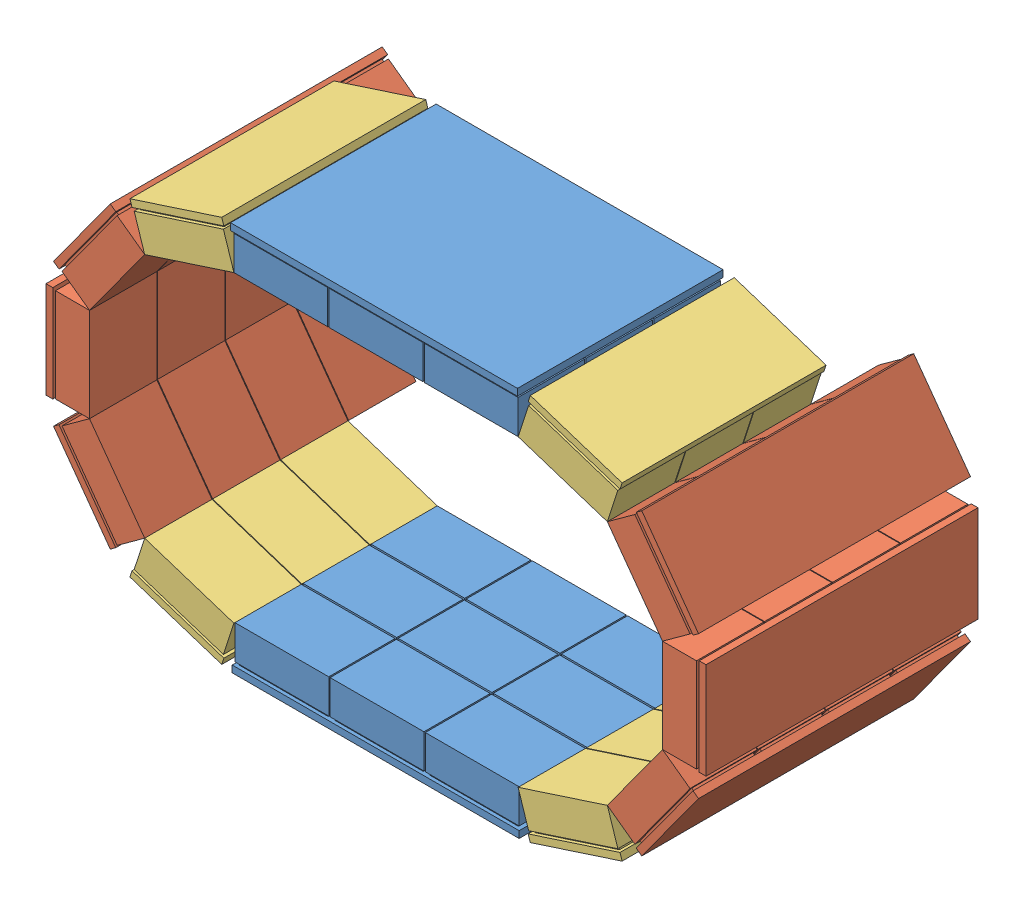
SolidWorks assembly Detector1n2_3_changed, configuration Default. Lengths in mm.
Overall size (565.24 340.33 201.48).
14 component instances, 3 part files, 18 mates.
Components (placement in the parent):
- top_bottomDetector3-2: top_bottomDetector3 [Default] at (-106.7647 78.2438 -235.0736) size (211 32 151.22)
- CshapedDetector2-3: CshapedDetector2 [Default] at (62.2764 -58.5479 -394.5758) x (0.951057 0.309017 0) z (0 0 1) size (177.89 270.84 200)
  - 1Detector-2: 1Detector [Default] at (173.0714 153.2337 184.2598) x (0.809017 0.587785 0) z (0 0 1) size (71 32 200)
  - 1Detector-4: 1Detector [Default] at (223.2683 222.3237 184.2598) x (0.309017 0.951057 0) z (0 0 1) size (71 32 200)
  - 1Detector-5: 1Detector [Default] at (223.2683 307.7237 184.2598) x (-0.309017 0.951057 0) z (0 0 1) size (71 32 200)
  - 1Detector_3modules-1: 1Detector_3modules [Default] at (91.8512 126.8436 209.2598) size (71 32 150)
  - 1Detector_3modules-2: 1Detector_3modules [Default] at (173.0714 376.8138 209.2598) x (-0.809017 0.587785 0) z (0 0 1) size (71 32 150)
- CshapedDetector2-4: CshapedDetector2 [Default] at (-135.8058 502.3243 -394.5758) x (-0.951057 -0.309017 0) z (0 0 1) size (177.89 270.84 200)
  - 1Detector-2: 1Detector [Default] at (173.0714 153.2337 184.2598) x (0.809017 0.587785 0) z (0 0 1) size (71 32 200)
  - 1Detector-4: 1Detector [Default] at (223.2683 222.3237 184.2598) x (0.309017 0.951057 0) z (0 0 1) size (71 32 200)
  - 1Detector-5: 1Detector [Default] at (223.2683 307.7237 184.2598) x (-0.309017 0.951057 0) z (0 0 1) size (71 32 200)
  - 1Detector_3modules-1: 1Detector_3modules [Default] at (91.8512 126.8436 209.2598) size (71 32 150)
  - 1Detector_3modules-2: 1Detector_3modules [Default] at (173.0714 376.8138 209.2598) x (-0.809017 0.587785 0) z (0 0 1) size (71 32 150)
- top_bottomDetector3-3: top_bottomDetector3 [Default] at (-106.7647 365.5325 -135.0585) x (1 0 0) z (0 0 -1) size (211 32 151.22)
Mates (geometry in assembly coordinates):
- Coincident2: coincident anti-aligned: line of ? through (109.8043 92.2155 198.3608) axis (0 0 -1); line of ? through (109.8043 92.2155 148.8608) axis (0 0 1)
- Angle1: planar angle = 3.455752 rad anti-aligned: line of ? through (40.8043 92.2155 198.3608) axis (1 0 0); line of ? through (109.8043 92.2155 198.3608) axis (0.951057 0.309017 0)
- Coincident4: coincident: point of ?; point of ?
- Coincident5: coincident anti-aligned: line of ? through (-29.1957 92.2155 149.6059) axis (0 0 1); line of ? through (-29.1957 92.2155 198.3608) axis (0 0 -1)
- Angle2: planar angle = 3.455752 rad anti-aligned: line of ? through (-94.8186 113.5376 198.3608) axis (0.951057 -0.309017 0); line of ? through (-29.1957 92.2155 198.3608) axis (1 0 0)
- Coincident7: coincident: point of ?; point of ?
- Coincident8: coincident anti-aligned: line of ? through (-29.1957 315.5042 198.3608) axis (0 0 -1); line of ? through (-29.1957 315.5042 148.8608) axis (0 0 1)
- Coincident11: coincident anti-aligned: line of ? through (109.8043 315.5042 198.3608) axis (0 0 -1); line of ? through (109.8043 315.5042 149.6059) axis (0 0 1)
- Coincident12: coincident: point of ?; point of ?
- Coincident14: coincident: line of top_bottomDetector3-2 through (67.7353 110.2438 -211.0612) axis (0 0 -1); line of CshapedDetector2-3/1Detector_3modules-1 through (67.7353 110.2438 -259.816) axis (0 0 1)
- Coincident16: coincident: point of top_bottomDetector3-2; point of CshapedDetector2-3/1Detector_3modules-1
- Angle4: planar angle = 3.455752 rad anti-aligned: line of top_bottomDetector3-2 through (67.7353 110.2438 -259.816) axis (-1 0 0); line of CshapedDetector2-3/1Detector_3modules-1 through (133.3582 131.566 -259.816) axis (-0.951057 -0.309017 0)
- Coincident18: coincident: line of top_bottomDetector3-2 through (-141.2647 110.2438 -259.816) axis (0 0 1); line of CshapedDetector2-4/1Detector_3modules-2 through (-141.2647 110.2438 -210.316) axis (0 0 -1)
- Coincident19: coincident: point of top_bottomDetector3-2; point of CshapedDetector2-4/1Detector_3modules-2
- Angle5: planar angle = 3.455752 rad anti-aligned: line of CshapedDetector2-4/1Detector_3modules-2 through (-141.2647 110.2438 -259.816) axis (-0.951057 0.309017 0); line of top_bottomDetector3-2 through (-72.2647 110.2438 -259.816) axis (-1 0 0)
- Coincident21: coincident: line of CshapedDetector2-4/1Detector_3modules-1 through (-141.2647 333.5325 -159.816) axis (0 0 1); moEndPointRef_w of top_bottomDetector3-3
- Coincident22: coincident: line of CshapedDetector2-3/1Detector_3modules-2 through (67.7353 333.5325 -110.316) axis (0 0 -1); line of top_bottomDetector3-3 through (67.7353 333.5325 -159.0709) axis (0 0 1)
- Coincident23: coincident: point of CshapedDetector2-4/1Detector_3modules-1; point of top_bottomDetector3-3
